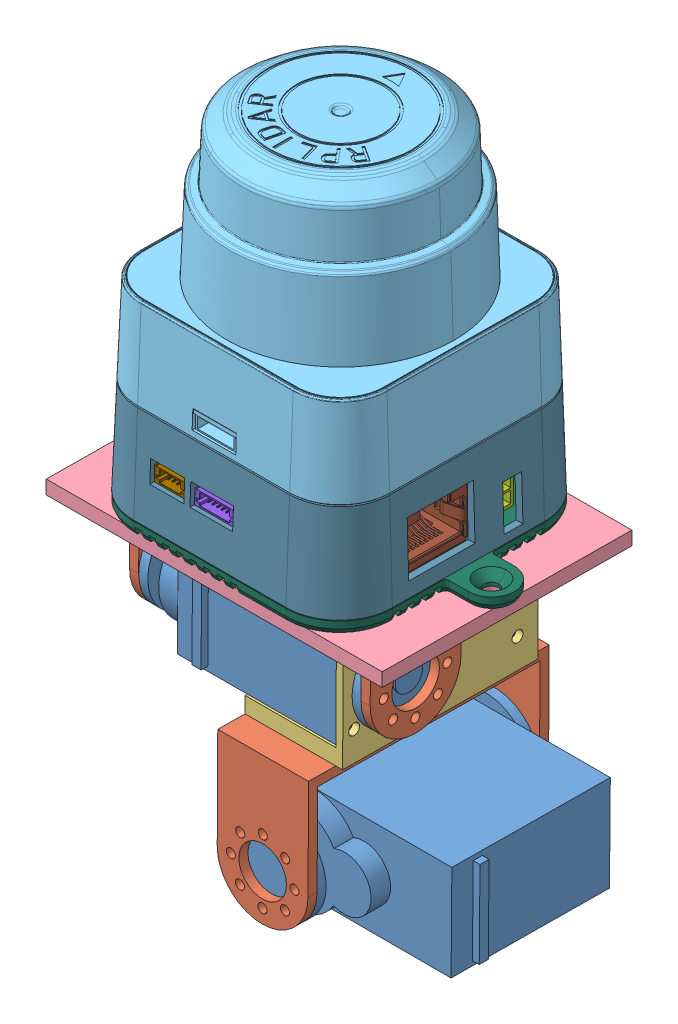
SolidWorks assembly 組合件1, configuration 預設. Lengths in mm.
Overall size (97.47 147.83 109.36).
20 component instances, 16 part files, 16 mates.
Components (placement in the parent):
- KRS_786-1: KRS_786 [預設] at (-139.2107 11.3616 165.7373) x (1 0 0) z (0 -0.008727 -0.999962) size (44 21 49.5)
- KRS_786-2: KRS_786 [預設] at (-174.2297 47.6444 150.0201) x (0 -0.008727 -0.999962) z (0.999995 0.003262 -0.000028) size (44 21 49.5)
- MotorRotate-1: MotorRotate [預設] at (-149.2825 33.2263 150.1459) x (0 -0.008727 -0.999962) z (0.003263 -0.999957 0.008726) size (53 20 32)
- MotorRotate2-1: MotorRotate2 [預設] at (-149.2825 33.2263 150.1459) x (0.999995 0.003262 -0.000028) z (-0.003263 0.999957 -0.008726) size (21.5 43 25)
- M2M1_base2-1: M2M1_base2 [預設] at (-149.4114 72.8118 159.8026) x (-0.999995 -0.003262 0.000028) z (0.003263 -0.999957 0.008657) size (74 55 3)
- MotorRotate-2: MotorRotate [預設] at (-158.9015 69.781 159.8288) x (-0.999995 -0.003262 0.000028) z (0.003263 -0.999957 0.008657) size (53 20 32)
- SLAMTEC MAPPER M2M1_IGS-1: SLAMTEC MAPPER M2M1_IGS [預設] at (-149.4894 96.7108 159.5957) x (-0.999995 -0.003262 0.000028) z (0.003263 -0.999957 0.008657) size (97.23 108.71 74.91)
  - SLAMTEC MAPPER M2M1_IGS(2)^SLAMTEC MAPPER M2M1_IGS-1: SLAMTEC MAPPER M2M1_IGS(2)^SLAMTEC MAPPER M2M1_IGS [預設] at origin size (97.23 108.71 74.91) (virtual)
    - rplidar-s1m1-r1^SLAMTEC MAPPER M2M1_IGS(2)_SLAMTEC MAPPER M2M1_IGS-1: rplidar-s1m1-r1^SLAMTEC MAPPER M2M1_IGS(2)_SLAMTEC MAPPER M2M1_IGS [預設] at origin size (97.23 108.71 51.5) (virtual)
    - 厙釐曹揤 ^SLAMTEC MAPPER M2M1_IGS(2)_SLAMTEC MAPPER M2M1_IGS-1: 厙釐曹揤 ^SLAMTEC MAPPER M2M1_IGS(2)_SLAMTEC MAPPER M2M1_IGS [預設] at (-6.25 -5.803 2.75) x (0 1 0) z (0 0 1) size (12.81 9.31 5.66) (virtual)
    - DC脣釱^SLAMTEC MAPPER M2M1_IGS(2)_SLAMTEC MAPPER M2M1_IGS-1: DC脣釱^SLAMTEC MAPPER M2M1_IGS(2)_SLAMTEC MAPPER M2M1_IGS [預設] at (-21.55 9.972 13.335) x (0 -1 0) z (-1 0 0) size (7.16 11.96 12.25) (virtual)
    - User Library-JST - SM06B-SRSS-TB (SH SERIES - 1_0mm PITCH WIRE-TO-BOARD, SMT, RA)^SLAMTEC MAPPER M2M1_IGS(2)_SLAMTEC MAPPER M2M1_IGS-1: User Library-JST - SM06B-SRSS-TB (SH SERIES - 1_0mm PITCH WIRE-TO-BOARD, SMT, RA)^SLAMTEC MAPPER M2M1_IGS(2)_SLAMTEC MAPPER M2M1_IGS [預設] at (0 -23.25 9.4) x (1 0 0) z (0 -1 0) size (8.81 3.31 4.96) (virtual)
    - User Library-JST - SM04B-SRSS-TB (SH SERIES - 1_0mm PITCH WIRE-TO-BOARD, SMT, RA)^SLAMTEC MAPPER M2M1_IGS(2)_SLAMTEC MAPPER M2M1_IGS-1: User Library-JST - SM04B-SRSS-TB (SH SERIES - 1_0mm PITCH WIRE-TO-BOARD, SMT, RA)^SLAMTEC MAPPER M2M1_IGS(2)_SLAMTEC MAPPER M2M1_IGS [預設] at (9.8 -23.25 9.4) x (1 0 0) z (0 -1 0) size (6.91 3.31 4.96) (virtual)
    - 綻蟯邧伎LED^SLAMTEC MAPPER M2M1_IGS(2)_SLAMTEC MAPPER M2M1_IGS-1: 綻蟯邧伎LED^SLAMTEC MAPPER M2M1_IGS(2)_SLAMTEC MAPPER M2M1_IGS [預設] at (-4 23.52 7.9) x (1 0 0) z (0 1 0) size (3.21 1.01 1.49) (virtual)
    - RJ45 1X1 SMT 8P8C-B脣釱 LCP窪遠悵__J17 DJ^SLAMTEC MAPPER M2M1_IGS(2)_SLAMTEC MAPPER M2M1_IGS-1: RJ45 1X1 SMT 8P8C-B脣釱 LCP窪遠悵__J17 DJ^SLAMTEC MAPPER M2M1_IGS(2)_SLAMTEC MAPPER M2M1_IGS [預設] at (-12.775 2.597 6.35) x (0 -1 0) z (0 0 -1) size (18.41 15.1 11.62) (virtual)
    - K2-1823SA葩弇羲壽^SLAMTEC MAPPER M2M1_IGS(2)_SLAMTEC MAPPER M2M1_IGS-1: K2-1823SA葩弇羲壽^SLAMTEC MAPPER M2M1_IGS(2)_SLAMTEC MAPPER M2M1_IGS [預設] at (4 23.75 7.1) x (-1 0 0) z (0 0 1) size (4.01 3.21 1.81) (virtual)
    - BAT_COVER1^SLAMTEC MAPPER M2M1_IGS(2)_SLAMTEC MAPPER M2M1_IGS-1: BAT_COVER1^SLAMTEC MAPPER M2M1_IGS(2)_SLAMTEC MAPPER M2M1_IGS [預設] at (0 -0.1187 -3.4) x (1 0 0) z (0 1 0) size (18.02 6.02 0.42) (virtual)
    - Mapper2-奻褲^SLAMTEC MAPPER M2M1_IGS(2)_SLAMTEC MAPPER M2M1_IGS-1: Mapper2-奻褲^SLAMTEC MAPPER M2M1_IGS(2)_SLAMTEC MAPPER M2M1_IGS [預設] x (1 0 0) z (0 1 0) size (57.05 23.13 57.05) (virtual)
    - MP2-底板-1031^SLAMTEC MAPPER M2M1_IGS(2)_SLAMTEC MAPPER M2M1_IGS-1: MP2-底板-1031^SLAMTEC MAPPER M2M1_IGS(2)_SLAMTEC MAPPER M2M1_IGS [預設] at (0 0 -1.6) x (1 0 0) z (0 1 0) size (77.12 5.51 57) (virtual)
    - Thermal pad_pad^SLAMTEC MAPPER M2M1_IGS(2)_SLAMTEC MAPPER M2M1_IGS-1: Thermal pad_pad^SLAMTEC MAPPER M2M1_IGS(2)_SLAMTEC MAPPER M2M1_IGS [預設] at (2 2.4517 21.4) x (-1 0 0) z (0 1 0) size (24.01 1.76 15.01) (virtual)
Mates (geometry in assembly coordinates):
- 重合/共線/共點1: coincident: plane of KRS_786-1 through (-149.2107 11.441 174.837) normal (0 0.008727 0.999962); plane of MotorRotate-1 through (-139.1782 1.4741 174.9239) normal (0 -0.008727 -0.999962)
- 重合/共線/共點2: coincident: plane of KRS_786-2 through (-139.3299 47.7583 150.0191) normal (0.999995 0.003262 -0.000028); plane of MotorRotate2-1 through (-139.3641 58.2578 149.9275) normal (-0.999995 -0.003262 0.000028)
- 重合/共線/共點3: coincident: plane of M2M1_base2-1 through (-149.4114 72.8118 159.8026) normal (-0.003263 0.999957 -0.008657); line of SLAMTEC MAPPER M2M1_IGS-1/SLAMTEC MAPPER M2M1_IGS(2)^SLAMTEC MAPPER M2M1_IGS-1/rplidar-s1m1-r1^SLAMTEC MAPPER M2M1_IGS(2)_SLAMTEC MAPPER M2M1_IGS-1 through (-182.9644 72.7024 159.8035) axis (0.999995 0.003262 -0.000028)
- 重合/共線/共點4: coincident: plane of M2M1_base2-1 through (-149.4016 69.812 159.8285) normal (0.003263 -0.999957 0.008657); plane of MotorRotate-2 through (-158.9015 69.781 159.8288) normal (-0.003263 0.999957 -0.008657)
- 重合/共線/共點5: coincident: plane of MotorRotate-1 through (-149.2825 33.2263 150.1459) normal (-0.003263 0.999957 -0.008726); plane of MotorRotate2-1 through (-149.2825 33.2263 150.1459) normal (0.003263 -0.999957 0.008726)
- 重合/共線/共點6: coincident: plane of KRS_786-2 through (-183.3296 47.702 160.02) normal (-0.999995 -0.003262 0.000028); plane of MotorRotate-2 through (-183.297 37.6159 150.1069) normal (0.999995 0.003262 -0.000028)
- 同軸心1: concentric: circle of MotorRotate-1; circle of MotorRotate2-1
- 同軸心2: concentric: cylinder of KRS_786-2 through (-149.3037 39.5689 132.0899) axis (0.999995 0.003262 -0.000028) radius 1; cylinder of MotorRotate2-1 through (-159.3037 39.5363 132.0902) axis (0.999995 0.003262 -0.000028) radius 1.2
- 同軸心3: concentric: circle of KRS_786-1; circle of MotorRotate-1
- 同軸心4: concentric: cylinder of KRS_786-2 through (-149.3559 55.8824 167.9489) axis (0.999995 0.003262 -0.000028) radius 1; cylinder of MotorRotate2-1 through (-159.3559 55.8498 167.9492) axis (0.999995 0.003262 -0.000028) radius 1.2
- 同軸心5: concentric: circle of MotorRotate-1; circle of MotorRotate2-1
- 同軸心6: concentric: cylinder of M2M1_base2-1 through (-151.9114 72.8037 159.8026) axis (0.003263 -0.999957 0.008657) radius 1.3; cylinder of MotorRotate-2 through (-151.7972 37.8052 160.1056) axis (-0.003263 0.999957 -0.008657) radius 1.3
- 同軸心7: concentric: cylinder of M2M1_base2-1 through (-126.4115 72.8869 159.8019) axis (0.003263 -0.999957 0.008657) radius 1.6; circle of SLAMTEC MAPPER M2M1_IGS-1/SLAMTEC MAPPER M2M1_IGS(2)^SLAMTEC MAPPER M2M1_IGS-1/rplidar-s1m1-r1^SLAMTEC MAPPER M2M1_IGS(2)_SLAMTEC MAPPER M2M1_IGS-1
- 同軸心8: concentric: cylinder of M2M1_base2-1 through (-172.4113 72.7368 159.8032) axis (0.003263 -0.999957 0.008657) radius 1.6; circle of SLAMTEC MAPPER M2M1_IGS-1/SLAMTEC MAPPER M2M1_IGS(2)^SLAMTEC MAPPER M2M1_IGS-1/rplidar-s1m1-r1^SLAMTEC MAPPER M2M1_IGS(2)_SLAMTEC MAPPER M2M1_IGS-1
- 同軸心9: concentric: cylinder of M2M1_base2-1 through (-165.9113 72.758 159.803) axis (0.003263 -0.999957 0.008657) radius 1.3; cylinder of MotorRotate-2 through (-165.7971 37.7595 160.106) axis (-0.003263 0.999957 -0.008657) radius 1.3
- 同軸心10: concentric: cylinder of KRS_786-2 through (-183.3296 47.702 160.02) axis (0.999995 0.003262 -0.000028) radius 10; cylinder of MotorRotate-2 through (-132.3289 47.8684 160.0185) axis (-0.999995 -0.003262 0.000028) radius 5.25
